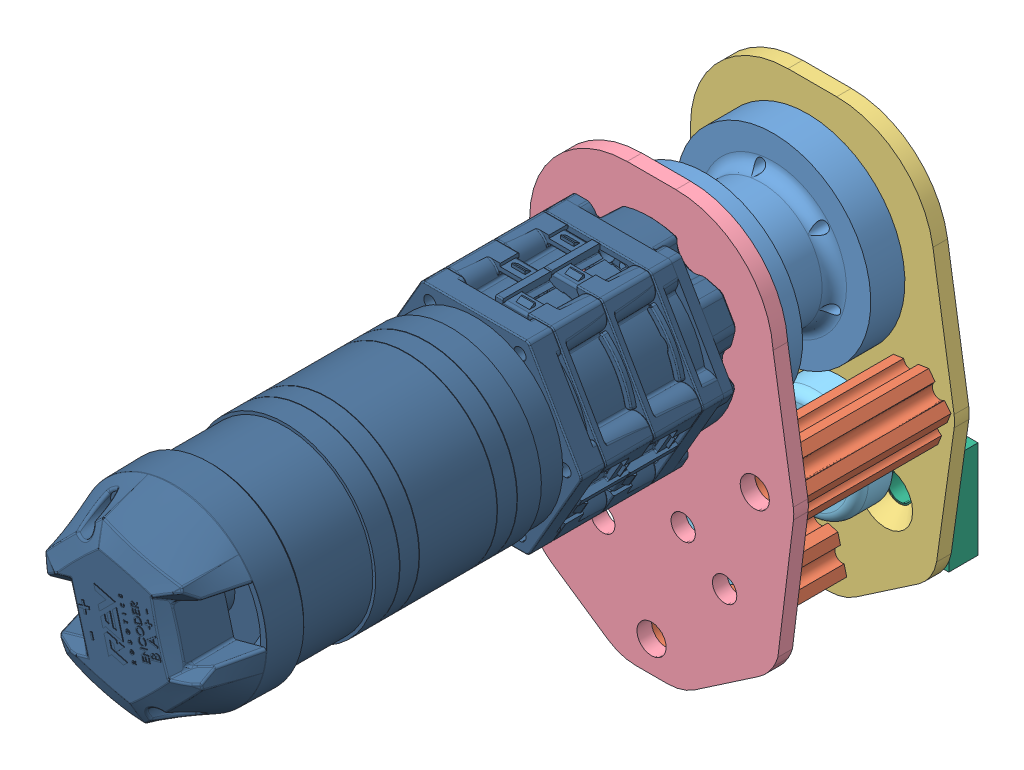
SolidWorks assembly Carretel, configuration Valor predeterminado. Lengths in mm.
Overall size (57.46 95.57 152.43).
13 component instances, 10 part files, 21 mates.
Components (placement in the parent):
- M04.05.02 Rolete-1: M04.05.02 Rolete [Valor predeterminado] at (-6.1608 21.8076 8.2875) x (0.985364 0.170465 0) z (0 0 1) size (40 40 29)
- M04.05.08 Churros carretel-1: M04.05.08 Churros carretel [Valor predeterminado] at (-18.3033 -5.1995 11.2875) x (0.786602 0.617461 0) z (0 0 -1) size (14.66 12.7 30)
- M04.05.04 Lateral mancal-1: M04.05.04 Lateral mancal [Valor predeterminado] at (18.8392 46.8076 -18.7125) x (0 -1 0) z (0 0 -1) size (88.7 54.19 3)
- M04.05.05 Lateral motor-1: M04.05.05 Lateral motor [Valor predeterminado] at (18.8392 46.8076 14.2875) x (0 -1 0) z (0 0 -1) size (88.7 54.19 3)
- M04.05.06 Polia-1: M04.05.06 Polia [Valor predeterminado] at (0.3392 -12.4424 10.2875) x (0.36588 0.930662 0) z (0 0 1) size (22 22 28)
- M04.05.07 Fixacao tubo-1: M04.05.07 Fixacao tubo [Valor predeterminado] at (18.8392 -9.1924 -21.7125) x (0 -1 0) z (0 0 -1) size (20 50 6)
- M04.05.08 Churros carretel-2: M04.05.08 Churros carretel [Valor predeterminado] at (-6.1608 -35.5424 11.2875) x (-0.715628 -0.698482 0) z (0 0 -1) size (14.66 12.7 30)
- M04.05.08 Churros carretel-3: M04.05.08 Churros carretel [Valor predeterminado] at (15.0318 1.1268 11.2875) x (-0.36588 -0.930662 0) z (0 0 -1) size (14.66 12.7 30)
- Mancal REV-1: Mancal REV [Valor predeterminado] at (-6.1608 21.8076 -26.2125) x (0 1 0) z (0 0 1) size (22 32.5 4.5)
  - REV-41-1683-1^Mancal REV-1: REV-41-1683-1^Mancal REV [Valor predeterminado] at origin size (22 32.5 4.5) (virtual)
  - REV-41-1527^Mancal REV-1: REV-41-1527^Mancal REV [Valor predeterminado] x (0.784162 -0.620556 0) z (0 0 1) size (9 9 4.5) (virtual)
  - 679ZZ.STEP-1: 679ZZ.STEP [Valor predeterminado] at (0 0 2.25) size (14 14 4.5)
- M04.05.09 HD HEX 2 Gear box5-1: M04.05.09 HD HEX 2 Gear box5 [Valor predeterminado] at (-6.1357 21.8422 72.7309) x (0.866025 -0.5 0) z (-0.5 -0.866025 0) size (38.85 117.43 43.57)
Mates (geometry in assembly coordinates):
- Concêntrico1: concentric aligned: cylinder of Lateral motor-1 through (15.0318 1.1268 11.2875) axis (0 0 1) radius 3; cylinder of Churros carretel-3 through (15.0318 1.1268 -18.7125) axis (0 0 1) radius 3
- Coincidente7: coincident anti-aligned: plane of Lateral motor-1 through (18.8392 46.8076 11.2875) normal (0 0 -1); plane of Churros carretel-3 through (15.0318 1.1268 11.2875) normal (0 0 1)
- Coincidente8: coincident anti-aligned: plane of Churros carretel-1 through (-18.3033 -5.1995 11.2875) normal (0 0 1); plane of Lateral motor-1 through (18.8392 46.8076 11.2875) normal (0 0 -1)
- Coincidente9: coincident anti-aligned: circle of Lateral motor-1; cylinder of Churros carretel-2 through (-6.1608 -35.5424 -18.7125) axis (0 0 1) radius 3
- Coincidente10: coincident anti-aligned: plane of Lateral motor-1 through (18.8392 46.8076 11.2875) normal (0 0 -1); plane of Churros carretel-2 through (-6.1608 -35.5424 11.2875) normal (0 0 1)
- Concêntrico3: concentric anti-aligned: cylinder of Lateral motor-1 through (8.8392 -19.1924 21.2875) axis (0 0 -1) radius 2.5; cylinder of Fixacao tubo-1 through (8.8392 -19.1924 -31.7125) axis (0 0 1) radius 2.5
- Coincidente13: coincident anti-aligned: circle of Lateral mancal-1; circle of Churros carretel-2
- Concêntrico4: concentric anti-aligned: cylinder of Churros carretel-1 through (-18.3033 -5.1995 -18.7125) axis (0 0 1) radius 3; cylinder of Lateral mancal-1 through (-18.3033 -5.1995 -18.7125) axis (0 0 -1) radius 3
- Largura1: width anti-aligned: plane of Lateral mancal-1 through (18.8392 46.8076 -18.7125) normal (0 0 1); plane of M04.05.06 Polia-1 through (18.8392 46.8076 11.2875) normal (0 0 -1); plane of Lateral motor-1 through (-9.8981 -8.4178 -17.7125) normal (0 0 -1); plane of M04.05.06 Polia-1 through (-7.1061 -9.5154 10.2875) normal (0 0 1)
- Concêntrico5: concentric aligned: cylinder of Lateral motor-1 through (0.3392 -12.4424 11.2875) axis (0 0 1) radius 2.5; cylinder of M04.05.06 Polia-1 through (0.3392 -12.4424 10.2875) axis (0 0 1) radius 8
- Concêntrico6: concentric aligned: cylinder of M04.05.02 Rolete-1 through (-6.1608 21.8076 -38.8546) axis (0 0 1) radius 5; cylinder of Lateral mancal-1 through (-6.1608 21.8076 -21.7125) axis (0 0 1) radius 6
- Concêntrico7: concentric aligned: cylinder of Lateral mancal-1 through (-16.1608 13.8076 -18.7125) axis (0 0 -1) radius 1.5; cylinder of Mancal REV-1/REV-41-1683-1^Mancal REV-1 through (-16.1608 13.8076 -26.2125) axis (0 0 -1) radius 1.25
- Concêntrico8: concentric aligned: cylinder of Lateral mancal-1 through (-16.1608 29.8076 -18.7125) axis (0 0 -1) radius 1.5; cylinder of Mancal REV-1/REV-41-1683-1^Mancal REV-1 through (-16.1608 29.8076 -26.2125) axis (0 0 -1) radius 1.25
- Coincidente14: coincident anti-aligned: plane of Lateral mancal-1 through (18.8392 46.8076 -21.7125) normal (0 0 -1); plane of Mancal REV-1/REV-41-1683-1^Mancal REV-1 through (-6.1608 21.8076 -21.7125) normal (0 0 1)
- Coincidente15: coincident anti-aligned: plane of M04.05.02 Rolete-1 through (-9.5701 41.5148 -21.7125) normal (0 0 -1); plane of Mancal REV-1/REV-41-1527^Mancal REV-1 through (-6.1608 21.8076 -21.7125) normal (0 0 1)
- Concêntrico14: concentric anti-aligned: cylinder of Lateral motor-1 through (-20.0172 29.8076 11.2875) axis (0 0 1) radius 1.5; cylinder of HD HEX 2 Gear box5-1 through (-20.0172 29.8076 14.2875) axis (0 0 -1) radius 1.25
- Concêntrico15: concentric aligned: cylinder of Lateral motor-1 through (-6.1608 21.8076 11.2875) axis (0 0 1) radius 12; cylinder of HD HEX 2 Gear box5-1 through (-6.1608 21.8076 7.2875) axis (0 0 1) radius 11
- Coincidente19: coincident anti-aligned: plane of Lateral motor-1 through (18.8392 46.8076 14.2875) normal (0 0 1); plane of HD HEX 2 Gear box5-1 through (-6.1608 21.8076 14.2875) normal (0 0 -1)
- Coincidente20: coincident anti-aligned: plane of Lateral mancal-1 through (18.8392 46.8076 -21.7125) normal (0 0 -1); plane of Fixacao tubo-1 through (18.8392 -9.1924 -21.7125) normal (0 0 1)
- Concêntrico16: concentric anti-aligned: circle of Lateral mancal-1; cylinder of Churros carretel-3 through (15.0318 1.1268 -18.7125) axis (0 0 1) radius 3
- Concêntrico17: concentric aligned: cylinder of M04.05.02 Rolete-1 through (-7.5246 29.6905 -18.7125) axis (0 0 -1) radius 1.7; cylinder of HD HEX 2 Gear box5-1 through (-7.5246 29.6905 7.2875) axis (0 0 -1) radius 1.25
